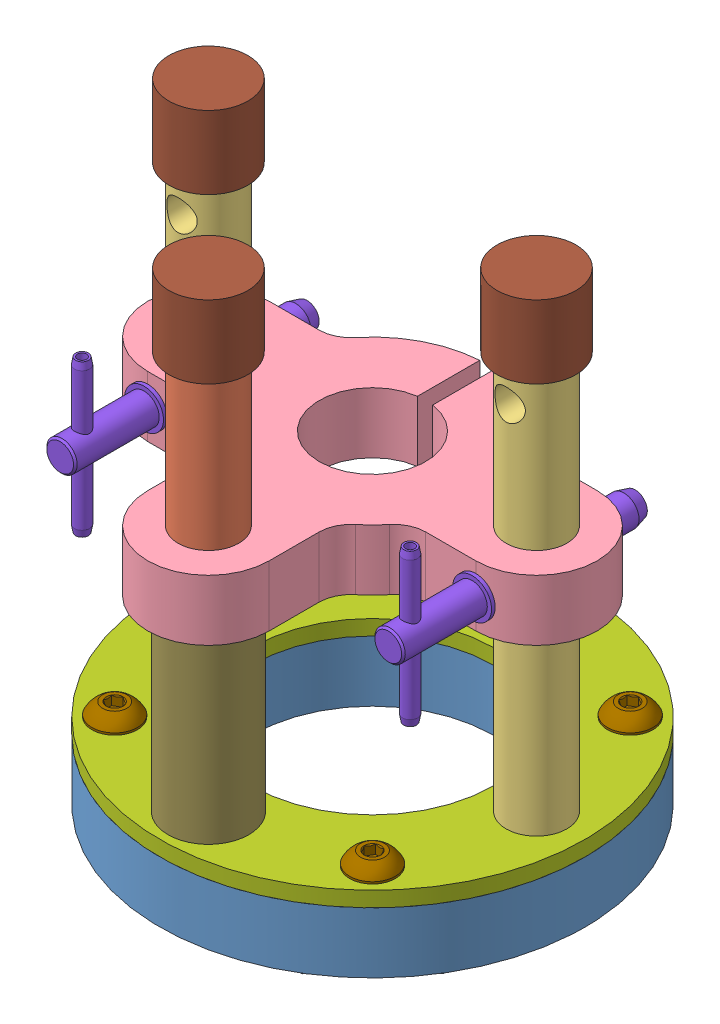
SolidWorks assembly Assemly-Béquile-Hivers, configuration Default. Lengths in mm.
Overall size (125.72 117.47 125.72).
38 component instances, 12 part files, 43 mates.
Components (placement in the parent):
- Base-Ring-1: Base-Ring [Default] x (1 0 0) z (0 1 0) size (88.9 88.9 12.7)
- Rear-Post-1: Rear-Post [Default] at (0 10.16 34.29) x (-0.010305 0 0.999947) z (0 1 0) size (12.7 12.7 101.6)
- Side-Post-1: Side-Post [Default] at (34.29 10.16 0) x (-1 0 0) z (0 1 0) size (12.7 12.7 101.6)
- Side-Post-2: Side-Post [Default] at (-34.29 10.16 0) x (1 0 0) z (0 1 0) size (12.7 12.7 101.6)
- Clamp-1: Clamp [Default] at (0 67.5844 0) x (-1 0 0) z (0 -1 0) size (93.98 71 12.7)
- 92200A540_Mil. Spec. 18-8 Stainless Steel Socket Head Screw-1: 92200A540_Mil. Spec. 18-8 Stainless Steel Socket Head Screw [92200A540] at (-2.2225 61.2344 -17.6641) x (0 0 -1) z (1 0 0) size (9.53 9.53 26.03)
- 92125A220_18-8 Stainless Steel Hex Drive Flat Head Screw-1: 92125A220_18-8 Stainless Steel Hex Drive Flat Head Screw [92125A220] at (0 15.46 34.29) x (1 0 0) z (0 -1 0) size (10 10 30.56)
- 92125A220_18-8 Stainless Steel Hex Drive Flat Head Screw-2: 92125A220_18-8 Stainless Steel Hex Drive Flat Head Screw [92125A220] at (34.29 15.46 0) x (1 0 0) z (0 -1 0) size (10 10 30.56)
- 92125A220_18-8 Stainless Steel Hex Drive Flat Head Screw-3: 92125A220_18-8 Stainless Steel Hex Drive Flat Head Screw [92125A220] at (-34.29 15.46 0) x (-0.914789 0 -0.403931) z (0 -1 0) size (10 10 30.56)
- Acrylic top sheet-1: Acrylic top sheet [Default] at (0 12.7 0) x (0.707107 0 -0.707107) z (0 1 0) size (88.9 88.9 3.17)
- 98325A130_Zinc-Plated Steel T-Handle Quick-Release Pin-1: 98325A130_Zinc-Plated Steel T-Handle Quick-Release Pin [98325A130] at (34.29 61.2344 5.1816) x (0 0 1) z (1 0 0) size (51.61 31.75 8.13)
- 98325A130_Zinc-Plated Steel T-Handle Quick-Release Pin-2: 98325A130_Zinc-Plated Steel T-Handle Quick-Release Pin [98325A130] at (-34.29 61.2344 5.1816) x (0 0 1) z (-1 0 0) size (51.61 31.75 8.13)
- 92095A210_Button Head Hex Drive Screw-1: 92095A210_Button Head Hex Drive Screw [92095A210] at (26.9408 18.625 -26.9408) x (1 0 0) z (0 1 0) size (9.5 9.5 15.22)
- 92095A210_Button Head Hex Drive Screw-2: 92095A210_Button Head Hex Drive Screw [92095A210] at (26.9408 18.625 26.9408) x (0 0 1) z (0 1 0) size (9.5 9.5 15.22)
- 92095A210_Button Head Hex Drive Screw-3: 92095A210_Button Head Hex Drive Screw [92095A210] at (-26.9408 18.625 26.9408) x (-1 0 0) z (0 1 0) size (9.5 9.5 15.22)
- 92095A210_Button Head Hex Drive Screw-4: 92095A210_Button Head Hex Drive Screw [92095A210] at (-26.9408 18.625 -26.9408) x (0 0 -1) z (0 1 0) size (9.5 9.5 15.22)
- 92785A513_18-8 Stainless Steel Cone-Point Set Screws-1: 92785A513_18-8 Stainless Steel Cone-Point Set Screws [92785A513] at (34.6453 4.7625 20.0025) x (1 0 0) z (0 1 0) size (3.57 3.51 16.26)
- 92785A513_18-8 Stainless Steel Cone-Point Set Screws-2: 92785A513_18-8 Stainless Steel Cone-Point Set Screws [92785A513] at (20.0025 4.7625 34.6453) x (0.866025 0 0.5) z (0 1 0) size (3.57 3.51 16.26)
- 92785A513_18-8 Stainless Steel Cone-Point Set Screws-4: 92785A513_18-8 Stainless Steel Cone-Point Set Screws [92785A513] at (-20.0025 4.7625 34.6453) x (0 0 1) z (0 1 0) size (3.57 3.51 16.26)
- 92785A513_18-8 Stainless Steel Cone-Point Set Screws-5: 92785A513_18-8 Stainless Steel Cone-Point Set Screws [92785A513] at (-34.6453 4.7625 20.0025) x (-0.5 0 0.866025) z (0 1 0) size (3.57 3.51 16.26)
- 92785A513_18-8 Stainless Steel Cone-Point Set Screws-7: 92785A513_18-8 Stainless Steel Cone-Point Set Screws [92785A513] at (-34.6453 4.7625 -20.0025) x (-1 0 0) z (0 1 0) size (3.57 3.51 16.26)
- 92785A513_18-8 Stainless Steel Cone-Point Set Screws-8: 92785A513_18-8 Stainless Steel Cone-Point Set Screws [92785A513] at (-20.0025 4.7625 -34.6453) x (-0.866025 0 -0.5) z (0 1 0) size (3.57 3.51 16.26)
- 92785A513_18-8 Stainless Steel Cone-Point Set Screws-9: 92785A513_18-8 Stainless Steel Cone-Point Set Screws [92785A513] at (0 4.7625 -40.005) x (-0.5 0 -0.866025) z (0 1 0) size (3.57 3.51 16.26)
- 92785A513_18-8 Stainless Steel Cone-Point Set Screws-10: 92785A513_18-8 Stainless Steel Cone-Point Set Screws [92785A513] at (20.0025 4.7625 -34.6453) x (0 0 -1) z (0 1 0) size (3.57 3.51 16.26)
- 92785A513_18-8 Stainless Steel Cone-Point Set Screws-11: 92785A513_18-8 Stainless Steel Cone-Point Set Screws [92785A513] at (34.6453 4.7625 -20.0025) x (0.5 0 -0.866025) z (0 1 0) size (3.57 3.51 16.26)
- 92785A513_18-8 Stainless Steel Cone-Point Set Screws-13: 92785A513_18-8 Stainless Steel Cone-Point Set Screws [92785A513] at (27.1869 4.7625 -12.6774) x (0.5 0 -0.866025) z (0 1 0) size (3.57 3.51 16.26)
- 92785A513_18-8 Stainless Steel Cone-Point Set Screws-15: 92785A513_18-8 Stainless Steel Cone-Point Set Screws [92785A513] at (24.5724 4.7625 17.2058) x (1 0 0) z (0 1 0) size (3.57 3.51 16.26)
- 92785A513_18-8 Stainless Steel Cone-Point Set Screws-16: 92785A513_18-8 Stainless Steel Cone-Point Set Screws [92785A513] at (12.6774 4.7625 27.1869) x (0.866025 0 0.5) z (0 1 0) size (3.57 3.51 16.26)
- 92785A513_18-8 Stainless Steel Cone-Point Set Screws-18: 92785A513_18-8 Stainless Steel Cone-Point Set Screws [92785A513] at (-17.2058 4.7625 24.5724) x (0 0 1) z (0 1 0) size (3.57 3.51 16.26)
- 92785A513_18-8 Stainless Steel Cone-Point Set Screws-19: 92785A513_18-8 Stainless Steel Cone-Point Set Screws [92785A513] at (-27.1869 4.7625 12.6774) x (-0.5 0 0.866025) z (0 1 0) size (3.57 3.51 16.26)
- 92785A513_18-8 Stainless Steel Cone-Point Set Screws-21: 92785A513_18-8 Stainless Steel Cone-Point Set Screws [92785A513] at (-24.5724 4.7625 -17.2058) x (-1 0 0) z (0 1 0) size (3.57 3.51 16.26)
- 92785A513_18-8 Stainless Steel Cone-Point Set Screws-22: 92785A513_18-8 Stainless Steel Cone-Point Set Screws [92785A513] at (-12.6774 4.7625 -27.1869) x (-0.866025 0 -0.5) z (0 1 0) size (3.57 3.51 16.26)
- 92785A513_18-8 Stainless Steel Cone-Point Set Screws-23: 92785A513_18-8 Stainless Steel Cone-Point Set Screws [92785A513] at (2.6144 4.7625 -29.8833) x (-0.5 0 -0.866025) z (0 1 0) size (3.57 3.51 16.26)
- 92785A513_18-8 Stainless Steel Cone-Point Set Screws-24: 92785A513_18-8 Stainless Steel Cone-Point Set Screws [92785A513] at (17.2058 4.7625 -24.5724) x (0 0 -1) z (0 1 0) size (3.57 3.51 16.26)
- Top Cap-1: Top Cap [Default] at (-34.29 99.06 0) x (1 0 0.000071) z (-0.000071 0 1) size (16.51 15.24 16.51)
- Top Cap-2: Top Cap [Default] at (0 99.06 34.29) x (1 0 0.000071) z (-0.000071 0 1) size (16.51 15.24 16.51)
- Top Cap-3: Top Cap [Default] at (34.29 99.06 0) x (1 0 0.000071) z (-0.000071 0 1) size (16.51 15.24 16.51)
- bottom spacer-1: bottom spacer [Default] at (0 53.975 34.29) x (1 0 0) z (0 -1 0) size (16.89 16.89 38.1)
Mates (geometry in assembly coordinates):
- Coincident1: coincident anti-aligned: plane of Base-Ring-1 through (0 0 0) normal (0 -1 0)
- Coincident2: coincident anti-aligned: plane of Base-Ring-1 through (0 0 0) normal (0 0 -1)
- Coincident4: coincident aligned: plane of Base-Ring-1 through (0 0 0) normal (1 0 0)
- Concentric2: concentric anti-aligned: circle of Base-Ring-1; circle of Acrylic top sheet-1
- Concentric3: concentric anti-aligned: cylinder of Base-Ring-1 through (-26.9408 12.7 26.9408) axis (0 1 0) radius 2.1; cylinder of Acrylic top sheet-1 through (-26.9408 12.7 26.9408) axis (0 -1 0) radius 2.6098
- Coincident8: coincident anti-aligned: plane of Base-Ring-1 through (0 12.7 0) normal (0 1 0); plane of Acrylic top sheet-1 through (0 12.7 0) normal (0 -1 0)
- Concentric4: concentric anti-aligned: cylinder of Rear-Post-1 through (0 111.76 34.29) axis (0 -1 0) radius 6.35; cylinder of Acrylic top sheet-1 through (0 12.7 34.29) axis (0 1 0) radius 6.35
- Coincident9: coincident anti-aligned: plane of Base-Ring-1 through (0 10.16 34.29) normal (0 1 0); plane of Rear-Post-1 through (0 10.16 34.29) normal (0 -1 0)
- Concentric5: concentric anti-aligned: cylinder of Base-Ring-1 through (-34.29 10.16 0) axis (0 1 0) radius 6.35; cylinder of Side-Post-2 through (-34.29 111.76 0) axis (0 -1 0) radius 6.35
- Coincident10: coincident aligned: plane of Base-Ring-1 through (-34.29 10.16 0) normal (0 1 0); circle of Side-Post-2
- Coincident11: coincident anti-aligned: plane of Side-Post-2 through (-34.29 10.16 0) normal (0 0 -1)
- Concentric6: concentric anti-aligned: cylinder of Base-Ring-1 through (34.29 10.16 0) axis (0 1 0) radius 6.35; cylinder of Side-Post-1 through (34.29 111.76 0) axis (0 -1 0) radius 6.35
- Coincident12: coincident anti-aligned: plane of Base-Ring-1 through (34.29 10.16 0) normal (0 1 0); plane of Side-Post-1 through (34.29 10.16 0) normal (0 -1 0)
- Coincident13: coincident aligned: plane of Side-Post-1 through (34.29 10.16 0) normal (0 0 1)
- Concentric7: concentric anti-aligned: cylinder of Side-Post-2 through (-34.29 111.76 0) axis (0 -1 0) radius 6.35; cylinder of Clamp-1 through (-34.29 54.8844 0) axis (0 1 0) radius 6.35
- Concentric8: concentric anti-aligned: cylinder of Side-Post-1 through (34.29 111.76 0) axis (0 -1 0) radius 6.35; cylinder of Clamp-1 through (34.29 54.8844 0) axis (0 1 0) radius 6.35
- Concentric10: concentric aligned: cone of Base-Ring-1 through (34.29 0 0) axis (0 1 0); cone of 92125A220_18-8 Stainless Steel Hex Drive Flat Head Screw-2 through (34.29 0.6 0) axis (0 1 0)
- Coincident15: coincident aligned: cone of Base-Ring-1 through (34.29 0 0) axis (0 1 0); cone of 92125A220_18-8 Stainless Steel Hex Drive Flat Head Screw-2 through (34.29 0.6 0) axis (0 1 0)
- Concentric11: concentric aligned: cone of Base-Ring-1 through (0 0 34.29) axis (0 1 0); cone of 92125A220_18-8 Stainless Steel Hex Drive Flat Head Screw-1 through (0 0.6 34.29) axis (0 1 0)
- Coincident17: coincident aligned: cone of Base-Ring-1 through (0 0 34.29) axis (0 1 0); cone of 92125A220_18-8 Stainless Steel Hex Drive Flat Head Screw-1 through (0 0.6 34.29) axis (0 1 0)
- Concentric12: concentric anti-aligned: cone of Base-Ring-1 through (-34.29 0 0) axis (0 1 0); circle of 92125A220_18-8 Stainless Steel Hex Drive Flat Head Screw-3
- Coincident19: coincident aligned: cone of Base-Ring-1 through (-34.29 0 0) axis (0 1 0); cone of 92125A220_18-8 Stainless Steel Hex Drive Flat Head Screw-3 through (-34.29 0.6 0) axis (0 1 0)
- Concentric13: concentric anti-aligned: cylinder of Clamp-1 through (46.99 61.2344 -17.6641) axis (-1 0 0) radius 4.7625; cylinder of 92200A540_Mil. Spec. 18-8 Stainless Steel Socket Head Screw-1 through (10.4775 61.2344 -17.6641) axis (1 0 0) radius 4.7625
- Coincident20: coincident anti-aligned: plane of Clamp-1 through (4.1275 61.2344 -17.6641) normal (1 0 0); plane of 92200A540_Mil. Spec. 18-8 Stainless Steel Socket Head Screw-1 through (4.1275 64.4094 -17.6641) normal (-1 0 0)
- Coincident21: coincident anti-aligned: plane of Clamp-1 through (-34.29 54.8844 12.7) normal (0 0 1); plane of 98325A130_Zinc-Plated Steel T-Handle Quick-Release Pin-2 through (-34.29 65.2984 12.7) normal (0 0 -1)
- Concentric15: concentric aligned: cylinder of Clamp-1 through (34.29 61.2344 46.99) axis (0 0 -1) radius 3.175; cylinder of 98325A130_Zinc-Plated Steel T-Handle Quick-Release Pin-1 through (34.29 61.2344 30.988) axis (0 0 -1) radius 3.175
- Coincident22: coincident anti-aligned: plane of Clamp-1 through (34.29 54.8844 12.7) normal (0 0 1); plane of 98325A130_Zinc-Plated Steel T-Handle Quick-Release Pin-1 through (34.29 57.1704 12.7) normal (0 0 -1)
- Concentric17: concentric aligned: cylinder of Base-Ring-1 through (26.9408 12.7 -26.9408) axis (0 1 0) radius 2.1; circle of 92095A210_Button Head Hex Drive Screw-1
- Coincident24: coincident anti-aligned: circle of Acrylic top sheet-1; plane of 92095A210_Button Head Hex Drive Screw-1 through (31.6908 15.875 -26.9408) normal (0 -1 0)
- Concentric18: concentric aligned: circle of Base-Ring-1; circle of 92785A513_18-8 Stainless Steel Cone-Point Set Screws-1
- Coincident25: coincident aligned: circle of Base-Ring-1; plane of 92785A513_18-8 Stainless Steel Cone-Point Set Screws-1 through (34.6453 12.7 20.0025) normal (0 1 0)
- Concentric19: concentric aligned: circle of Base-Ring-1; circle of 92785A513_18-8 Stainless Steel Cone-Point Set Screws-13
- Coincident26: coincident aligned: circle of Base-Ring-1; plane of 92785A513_18-8 Stainless Steel Cone-Point Set Screws-13 through (27.1869 12.7 -12.6774) normal (0 1 0)
- Concentric20: concentric aligned: cylinder of Side-Post-1 through (34.29 111.76 0) axis (0 -1 0) radius 6.35; cylinder of Top Cap-3 through (34.29 111.76 0) axis (0 -1 0) radius 8.255
- Coincident27: coincident anti-aligned: plane of Side-Post-1 through (34.29 111.76 0) normal (0 1 0); plane of Top Cap-3 through (34.29 111.76 0) normal (0 -1 0)
- Concentric21: concentric aligned: cylinder of Rear-Post-1 through (0 111.76 34.29) axis (0 -1 0) radius 6.35; cylinder of Top Cap-2 through (0 111.76 34.29) axis (0 -1 0) radius 8.255
- Coincident28: coincident anti-aligned: plane of Rear-Post-1 through (0 111.76 34.29) normal (0 1 0); plane of Top Cap-2 through (0 111.76 34.29) normal (0 -1 0)
- Concentric22: concentric aligned: cylinder of Side-Post-2 through (-34.29 111.76 0) axis (0 -1 0) radius 6.35; cylinder of Top Cap-1 through (-34.29 111.76 0) axis (0 -1 0) radius 8.255
- Coincident29: coincident anti-aligned: plane of Side-Post-2 through (-34.29 111.76 0) normal (0 1 0); plane of Top Cap-1 through (-34.29 111.76 0) normal (0 -1 0)
- Concentric23: concentric anti-aligned: cylinder of Rear-Post-1 through (0 111.76 34.29) axis (0 -1 0) radius 6.35; cylinder of bottom spacer-1 through (0 15.875 34.29) axis (0 1 0) radius 8.4455
- Coincident30: coincident anti-aligned: circle of Acrylic top sheet-1; plane of bottom spacer-1 through (0 15.875 34.29) normal (0 -1 0)
- LimitDistance2: limit distance = 31.4756 mm anti-aligned: plane of Clamp-1 through (0 67.5844 0) normal (0 1 0); plane of Top Cap-1 through (-34.29 99.06 0) normal (0 -1 0)
- Concentric24: concentric aligned: cylinder of Clamp-1 through (-34.29 61.2344 46.99) axis (0 0 -1) radius 3.175; cylinder of 98325A130_Zinc-Plated Steel T-Handle Quick-Release Pin-2 through (-34.29 61.2344 30.988) axis (0 0 -1) radius 3.175
